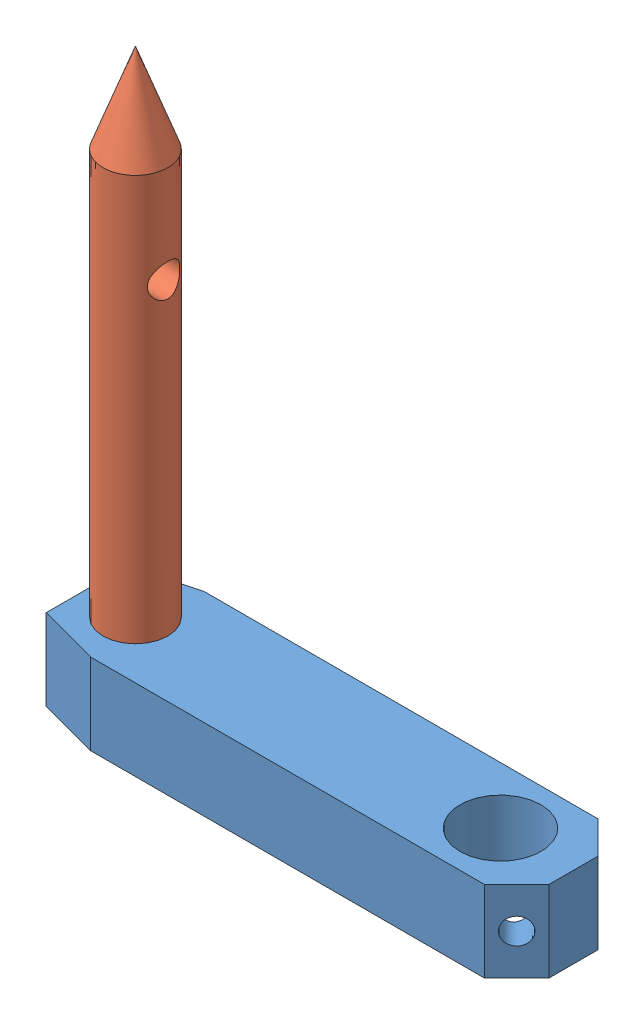
SolidWorks assembly beak_holder_with_bar, configuration starling_upper. Lengths in mm.
Overall size (30 35.49 7).
2 component instances, 2 part files, 3 mates.
Components (placement in the parent):
- block-1: block [starling_upper] at origin size (30 5 7)
- beak_bar-1: beak_bar [fusion] at (0 -5 0) x (0 0 1) z (-1 0 0) size (4 35.49 4)
Mates (geometry in assembly coordinates):
- Coincident1: coincident aligned: plane of block-1 through (0 -5 0) normal (0 -1 0); plane of beak_bar-1 through (0 -5 0) normal (0 -1 0)
- Concentric1: concentric aligned: circle of block-1; circle of beak_holder-1
- Perpendicular1: perpendicular: plane of block-1 through (0 0 0) normal (1 0 0); plane of beak_bar-1 through (0 -5 0) normal (0 0 1)
